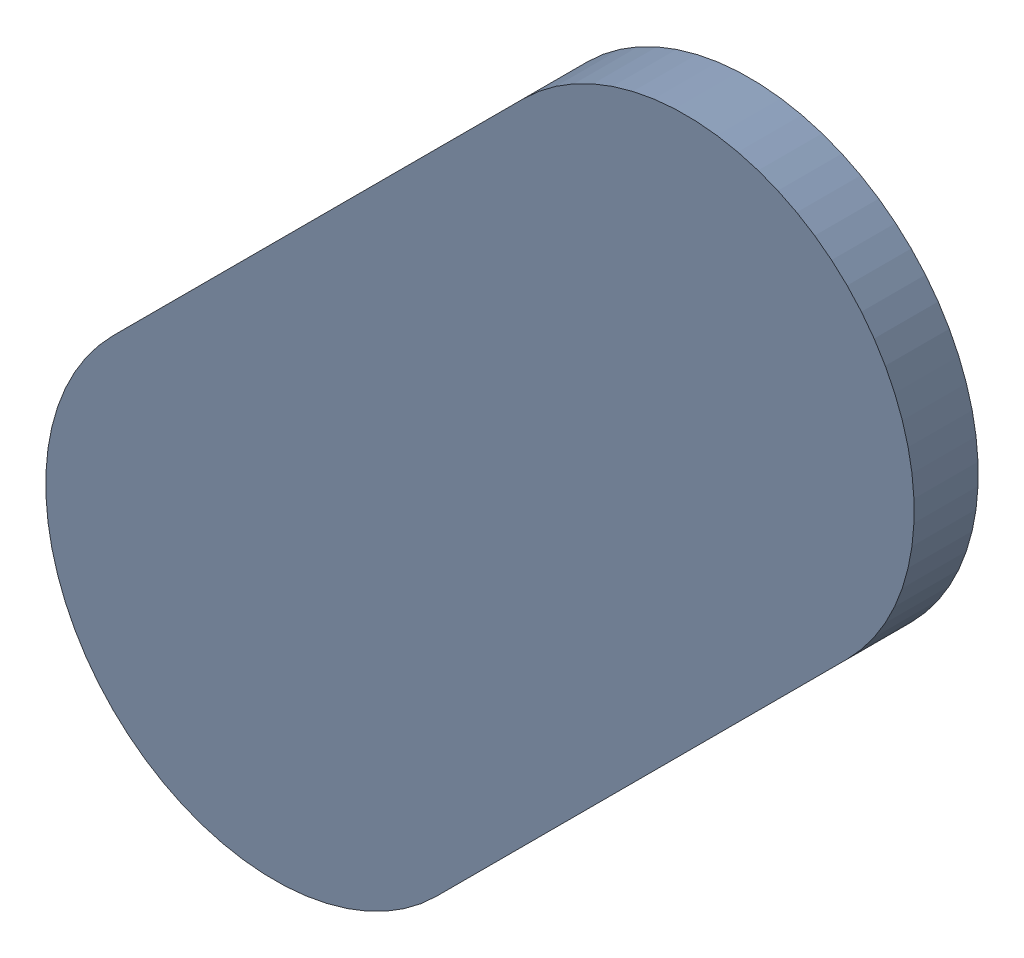
SolidWorks assembly Track (21.039mm,47.265mm)(21.267mm,47.493mm) on Bottom Layer, configuration Predeterminado. Lengths in mm.
Overall size (0.48 0.48 0.04).
2 component instances, 1 part files, 0 mates.
Components (placement in the parent):
- Track (21.039mm,47.265mm)(21.267mm,47.493mm) on Bottom Layer-1-1: Track (21.039mm,47.265mm)(21.267mm,47.493mm) on Bottom Layer-1 [Predeterminado] at (-68.317 -44.187 -0.4013) size (0.48 0.48 0.04)
  - Track (21.039mm,47.265mm)(21.267mm,47.493mm) on Bottom Layer-Part-1-1: Track (21.039mm,47.265mm)(21.267mm,47.493mm) on Bottom Layer-Part-1 [Predeterminado] at origin size (0.48 0.48 0.04)
